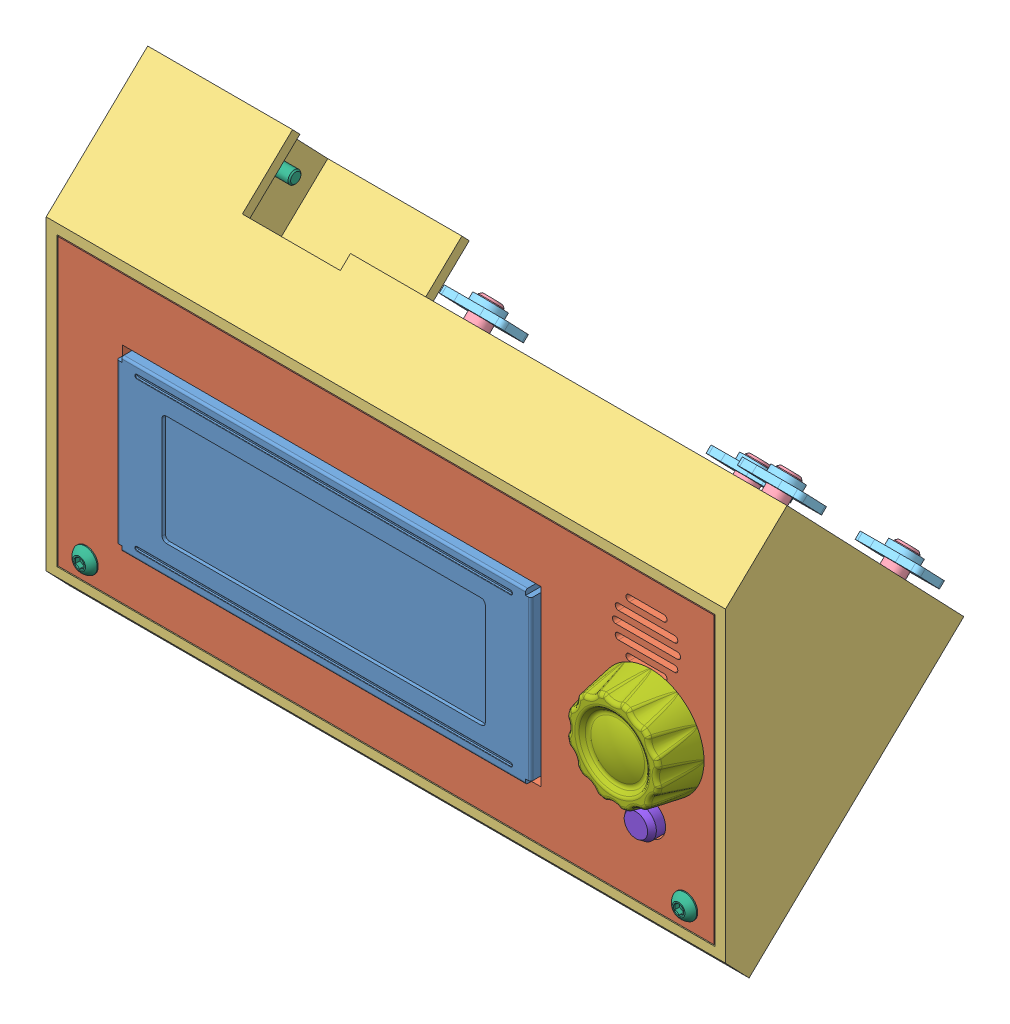
SolidWorks assembly Geetech_GT2560_LCD_Box_ASMB, configuration Default. Lengths in mm.
Overall size (160.65 100.6 74.43).
19 component instances, 8 part files, 39 mates.
Components (placement in the parent):
- Geetech_GT2560_LCD-1: Geetech_GT2560_LCD [Default] at origin size (150 63 27.4)
- Geetech_GT2560_LCD_Front_Cover-1: Geetech_GT2560_LCD_Front_Cover [Default] at (0 -4 14.1) size (154 69.05 12.2)
- Geetech_GT2560_LCD_Back_Cover-1: Geetech_GT2560_LCD_Back_Cover [Default] at (1.4199 -4.9021 12.2) size (159.5 100.6 65.33)
- Low Profile Screw M5-1: Low Profile Screw M5 [M5 x 8] at (69.75 42.5131 -13.1333) x (0 0.691661 -0.722222) z (0.786787 0.445773 0.42691) size (9.62 9 9)
- Low Profile Screw M5-2: Low Profile Screw M5 [M5 x 8] at (-0.25 42.5131 -13.1333) x (0 0.691661 -0.722222) z (0.722222 0.499533 0.478395) size (9.62 9 9)
- Low Profile Screw M5-3: Low Profile Screw M5 [M5 x 8] at (69.75 13.6242 -40.7997) x (0 0.691661 -0.722222) z (0.722222 0.499533 0.478395) size (9.62 9 9)
- Low Profile Screw M5-4: Low Profile Screw M5 [M5 x 8] at (34.75 13.6242 -40.7997) x (0 0.691661 -0.722222) z (0.722222 0.499533 0.478395) size (9.62 9 9)
- Tee Nut-1: Tee Nut [Default] at (-0.25 39.9539 -10.4611) x (1 0 0) z (0 0.691661 -0.722222) size (15 10 3)
- Tee Nut-2: Tee Nut [Default] at (69.75 39.9539 -10.4611) x (1 0 0) z (0 0.691661 -0.722222) size (15 10 3)
- Tee Nut-3: Tee Nut [Default] at (34.75 11.065 -38.1275) x (1 0 0) z (0 0.691661 -0.722222) size (15 10 3)
- Tee Nut-4: Tee Nut [Default] at (69.75 11.065 -38.1275) x (-1 0 0) z (0 0.691661 -0.722222) size (15 10 3)
- Button Head Socket Cap Screw M3-1: Button Head Socket Cap Screw M3 [M3 x 8] at (72.25 24.75 6.3) x (0 0 1) z (-1 0 0) size (9.65 5.7 5.7)
- Button Head Socket Cap Screw M3-2: Button Head Socket Cap Screw M3 [M3 x 8] at (-71.2453 19.2365 -37.8767) size (9.65 5.7 5.7)
- Button Head Socket Cap Screw M3-3: Button Head Socket Cap Screw M3 [M3 x 8] at (-72.25 -24.75 6.3) x (0 0 1) z (-1 0 0) size (9.65 5.7 5.7)
- Button Head Socket Cap Screw M3-4: Button Head Socket Cap Screw M3 [M3 x 8] at (72.25 -24.75 6.3) x (0 0 1) z (-1 0 0) size (9.65 5.7 5.7)
- Button Head Socket Cap Screw M3-5: Button Head Socket Cap Screw M3 [M3 x 8] at (-70.3766 -32.8766 4.2) x (0 0 -1) z (1 0 0) size (9.65 5.7 5.7)
- Button Head Socket Cap Screw M3-6: Button Head Socket Cap Screw M3 [M3 x 8] at (70.3766 -32.8766 4.2) x (0 0 -1) z (1 0 0) size (9.65 5.7 5.7)
- Geetech_GT2560_LCD_Knob-1: Geetech_GT2560_LCD_Knob [Default] at (62.3 -1.25 12.3) x (0 -1 0) z (0 0 -1) size (25.54 25.54 9)
- Reset Button-1: Reset Button [Default] at (61.7 -19.35 3.3) x (-0.923728 -0.383049 0) z (0 0 -1) size (12.2 12.2 11.9)
Mates (geometry in assembly coordinates):
- Concentric1: concentric anti-aligned: cylinder of Geetech_GT2560_LCD-1 through (72.25 24.75 0) axis (0 0 -1) radius 1.5; cylinder of Geetech_GT2560_LCD_Front_Cover-1 through (72.25 24.75 0) axis (0 0 1) radius 1.3
- Concentric2: concentric anti-aligned: cylinder of Geetech_GT2560_LCD-1 through (-72.25 -24.75 0) axis (0 0 -1) radius 1.5; cylinder of Geetech_GT2560_LCD_Front_Cover-1 through (-72.25 -24.75 0) axis (0 0 1) radius 1.3
- Coincident1: coincident anti-aligned: plane of Geetech_GT2560_LCD-1 through (0 0 0) normal (0 0 1); plane of Geetech_GT2560_LCD_Front_Cover-1 through (-72.25 -24.75 0) normal (0 0 -1)
- Coincident2: coincident aligned: plane of Geetech_GT2560_LCD_Front_Cover-1 through (0 -4 12.2) normal (0 0 1); plane of Geetech_GT2560_LCD_Back_Cover-1 through (79.75 32.0979 12.2) normal (0 0 1)
- Concentric31: concentric aligned: cylinder of Geetech_GT2560_LCD_Back_Cover-1 through (69.75 31.8934 -2.0443) axis (0 0.691661 -0.722222) radius 2.6; cylinder of Low Profile Screw M5-1 through (69.75 36.9798 -7.3555) axis (0 0.691661 -0.722222) radius 2.5
- Coincident31: coincident anti-aligned: plane of Geetech_GT2560_LCD_Back_Cover-1 through (79.75 44.202 -0.4389) normal (0 -0.691661 0.722222); plane of Low Profile Screw M5-1 through (67.1815 39.3445 -5.0909) normal (0 0.691661 -0.722222)
- Concentric41: concentric aligned: cylinder of Geetech_GT2560_LCD_Back_Cover-1 through (69.75 3.0045 -29.7108) axis (0 0.691661 -0.722222) radius 2.6; cylinder of Low Profile Screw M5-3 through (69.75 8.0909 -35.0219) axis (0 0.691661 -0.722222) radius 2.5
- Coincident41: coincident anti-aligned: plane of Geetech_GT2560_LCD_Back_Cover-1 through (79.75 44.202 -0.4389) normal (0 -0.691661 0.722222); plane of Low Profile Screw M5-3 through (66.8717 10.2615 -32.9432) normal (0 0.691661 -0.722222)
- Concentric51: concentric aligned: cylinder of Geetech_GT2560_LCD_Back_Cover-1 through (34.75 3.0045 -29.7108) axis (0 0.691661 -0.722222) radius 2.6; cylinder of Low Profile Screw M5-4 through (34.75 8.0909 -35.0219) axis (0 0.691661 -0.722222) radius 2.5
- Coincident51: coincident anti-aligned: plane of Geetech_GT2560_LCD_Back_Cover-1 through (79.75 44.202 -0.4389) normal (0 -0.691661 0.722222); plane of Low Profile Screw M5-4 through (31.8717 10.2615 -32.9432) normal (0 0.691661 -0.722222)
- Concentric6: concentric aligned: cylinder of Geetech_GT2560_LCD_Back_Cover-1 through (-0.25 31.8934 -2.0443) axis (0 0.691661 -0.722222) radius 2.6; cylinder of Low Profile Screw M5-2 through (-0.25 36.9798 -7.3555) axis (0 0.691661 -0.722222) radius 2.5
- Coincident6: coincident anti-aligned: plane of Geetech_GT2560_LCD_Back_Cover-1 through (79.75 44.202 -0.4389) normal (0 -0.691661 0.722222); plane of Low Profile Screw M5-2 through (-3.1283 39.1504 -5.2767) normal (0 0.691661 -0.722222)
- Concentric7: concentric aligned: cylinder of Low Profile Screw M5-2 through (-0.25 36.9798 -7.3555) axis (0 0.691661 -0.722222) radius 2.5; cylinder of Tee Nut-1 through (-0.25 42.0289 -12.6277) axis (0 0.691661 -0.722222) radius 2.1
- Concentric8: concentric aligned: cylinder of Low Profile Screw M5-1 through (69.75 36.9798 -7.3555) axis (0 0.691661 -0.722222) radius 2.5; cylinder of Tee Nut-2 through (69.75 42.0289 -12.6277) axis (0 0.691661 -0.722222) radius 2.1
- Concentric9: concentric aligned: cylinder of Low Profile Screw M5-4 through (34.75 8.0909 -35.0219) axis (0 0.691661 -0.722222) radius 2.5; cylinder of Tee Nut-3 through (34.75 13.14 -40.2942) axis (0 0.691661 -0.722222) radius 2.1
- Concentric10: concentric aligned: cylinder of Low Profile Screw M5-3 through (69.75 8.0909 -35.0219) axis (0 0.691661 -0.722222) radius 2.5; cylinder of Tee Nut-4 through (69.75 13.14 -40.2942) axis (0 0.691661 -0.722222) radius 2.1
- Parallel1: parallel aligned: plane of Geetech_GT2560_LCD_Back_Cover-1 through (79.75 32.0979 12.2) normal (0 0.722222 0.691661); plane of Tee Nut-1 through (-3.25 44.6717 -8.1583) normal (0 0.722222 0.691661)
- Parallel2: parallel aligned: plane of Geetech_GT2560_LCD_Back_Cover-1 through (79.75 32.0979 12.2) normal (0 0.722222 0.691661); plane of Tee Nut-2 through (66.75 44.6717 -8.1583) normal (0 0.722222 0.691661)
- Parallel3: parallel aligned: plane of Geetech_GT2560_LCD_Back_Cover-1 through (79.75 32.0979 12.2) normal (0 0.722222 0.691661); plane of Tee Nut-3 through (31.75 15.7828 -35.8247) normal (0 0.722222 0.691661)
- Parallel4: parallel aligned: plane of Geetech_GT2560_LCD_Back_Cover-1 through (79.75 32.0979 12.2) normal (0 0.722222 0.691661); plane of Tee Nut-4 through (72.75 15.7828 -35.8247) normal (0 0.722222 0.691661)
- Distance1: distance = 1.8 mm anti-aligned: plane of Geetech_GT2560_LCD_Back_Cover-1 through (79.75 45.9312 -2.2444) normal (0 0.691661 -0.722222); plane of Tee Nut-1 through (5.75 37.7873 -12.536) normal (0 -0.691661 0.722222)
- Distance2: distance = 1.8 mm anti-aligned: plane of Geetech_GT2560_LCD_Back_Cover-1 through (79.75 45.9312 -2.2444) normal (0 0.691661 -0.722222); plane of Tee Nut-2 through (75.75 37.7873 -12.536) normal (0 -0.691661 0.722222)
- Distance3: distance = 1.8 mm anti-aligned: plane of Geetech_GT2560_LCD_Back_Cover-1 through (79.75 45.9312 -2.2444) normal (0 0.691661 -0.722222); plane of Tee Nut-3 through (40.75 8.8984 -40.2025) normal (0 -0.691661 0.722222)
- Distance4: distance = 1.8 mm anti-aligned: plane of Geetech_GT2560_LCD_Back_Cover-1 through (79.75 45.9312 -2.2444) normal (0 0.691661 -0.722222); plane of Tee Nut-4 through (63.75 13.2317 -36.0525) normal (0 -0.691661 0.722222)
- Concentric111: concentric anti-aligned: cylinder of Geetech_GT2560_LCD-1 through (72.25 24.75 0) axis (0 0 -1) radius 1.5; cylinder of Button Head Socket Cap Screw M3-1 through (72.25 24.75 -1.7) axis (0 0 1) radius 2.85
- Coincident81: coincident anti-aligned: plane of Geetech_GT2560_LCD-1 through (0 0 -1.7) normal (0 0 -1); plane of Button Head Socket Cap Screw M3-1 through (72.25 27.6 -1.7) normal (0 0 1)
- Concentric121: concentric anti-aligned: cylinder of Geetech_GT2560_LCD-1 through (-72.25 -24.75 0) axis (0 0 -1) radius 1.5; cylinder of Button Head Socket Cap Screw M3-3 through (-72.25 -24.75 -1.7) axis (0 0 1) radius 2.85
- Coincident91: coincident anti-aligned: plane of Geetech_GT2560_LCD-1 through (0 0 -1.7) normal (0 0 -1); plane of Button Head Socket Cap Screw M3-3 through (-72.25 -21.9 -1.7) normal (0 0 1)
- Concentric131: concentric anti-aligned: cylinder of Geetech_GT2560_LCD-1 through (72.25 -24.75 0) axis (0 0 -1) radius 1.5; cylinder of Button Head Socket Cap Screw M3-4 through (72.25 -24.75 -1.7) axis (0 0 1) radius 2.85
- Coincident101: coincident anti-aligned: plane of Geetech_GT2560_LCD-1 through (0 0 -1.7) normal (0 0 -1); plane of Button Head Socket Cap Screw M3-4 through (72.25 -21.9 -1.7) normal (0 0 1)
- Concentric141: concentric anti-aligned: cylinder of Geetech_GT2560_LCD_Front_Cover-1 through (-70.3766 -32.8766 5.3917) axis (0 0 1) radius 1.7; cylinder of Button Head Socket Cap Screw M3-5 through (-70.3766 -32.8766 12.2) axis (0 0 -1) radius 2.85
- Coincident111: coincident anti-aligned: plane of Geetech_GT2560_LCD_Front_Cover-1 through (0 -4 12.2) normal (0 0 1); plane of Button Head Socket Cap Screw M3-5 through (-70.3766 -30.0266 12.2) normal (0 0 -1)
- Concentric151: concentric anti-aligned: cylinder of Geetech_GT2560_LCD_Front_Cover-1 through (70.3766 -32.8766 5.3917) axis (0 0 1) radius 1.7; cylinder of Button Head Socket Cap Screw M3-6 through (70.3766 -32.8766 12.2) axis (0 0 -1) radius 2.85
- Coincident121: coincident anti-aligned: plane of Geetech_GT2560_LCD_Front_Cover-1 through (0 -4 12.2) normal (0 0 1); plane of Button Head Socket Cap Screw M3-6 through (70.3766 -30.0266 12.2) normal (0 0 -1)
- Concentric153: concentric aligned: cylinder of Geetech_GT2560_LCD_Front_Cover-1 through (61.7 -19.35 12.2) axis (0 0 -1) radius 4; cylinder of Reset Button-1 through (61.7 -19.35 3.3) axis (0 0 -1) radius 3.6
- Coincident124: coincident anti-aligned: circle of Geetech_GT2560_LCD_Front_Cover-1; plane of Reset Button-1 through (58.3746 -20.729 10.2) normal (0 0 1)
- Concentric154: concentric aligned: cylinder of Geetech_GT2560_LCD-1 through (62.3 -1.25 16.7) axis (0 0 -1) radius 3; cylinder of Geetech_GT2560_LCD_Knob-1 through (62.3 -1.25 19.4608) axis (0 0 -1) radius 3.175
- Parallel5: parallel anti-aligned: plane of Geetech_GT2560_LCD-1 through (60.83 1.3652 11.6) normal (-1 0 0); plane of Geetech_GT2560_LCD_Knob-1 through (60.675 1.4776 500012.3) normal (1 0 0)
- Coincident126: coincident anti-aligned: plane of Geetech_GT2560_LCD-1 through (62.3 -1.25 16.7) normal (0 0 1); circle of Geetech_GT2560_LCD_Knob-1
